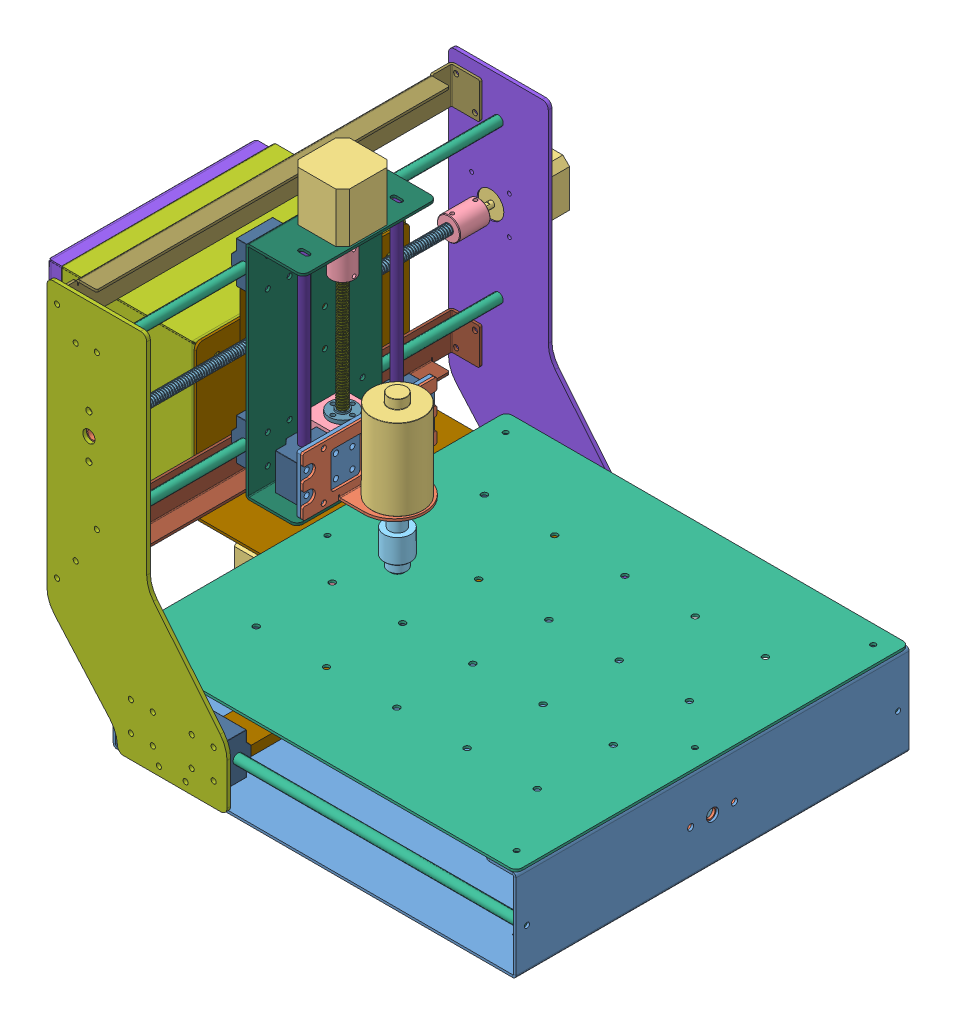
SolidWorks assembly MainAssem, configuration Default. Lengths in mm.
Overall size (517 348 374).
54 component instances, 27 part files, 15 mates.
Components (placement in the parent):
- SubAssem1-1: SubAssem1 [Default] at (69.9211 42.1369 -0.623) size (372 75 323) (flexible)
  - Base-1: Base [Default] at (143.0333 142.026 264.6541) size (331 75 323)
  - Pilow Bearing-1: Pilow Bearing [Default] at (306.5333 141.026 264.6541) x (0 0 -1) z (0 1 0) size (48 12 27)
  - Stepper Motor-1: Stepper Motor [Default] at (-41.9667 141.026 264.6541) x (0 -1 0) z (0 0 1) size (42 64 42)
  - Coupler-1: Coupler [Default] at (2.5333 141.026 264.6541) x (-1 0 0) z (0 0 -1) size (25 19 19)
  - Lead Screw 300mm-1: Lead Screw 300mm [Default] at (154.5333 141.026 264.6541) x (1 0 0) z (0 -0.67412 0.738622) size (304.2 8.95 8.95)
  - X-Y Rod-1: X-Y Rod [Default] at (143.0333 138.526 417.1541) x (0 0 -1) z (1 0 0) size (8 8 327)
  - X-Y Rod-2: X-Y Rod [Default] at (143.0333 138.526 112.1541) x (0 0 -1) z (1 0 0) size (8 8 327)
- SubAssem2-1: SubAssem2 [Default] at (9.4253 141.2294 165.1204) size (148 309 374) (flexible)
  - Leg B-1: Leg B [Default] at (29.5291 158.4335 263.9106) size (148 309 3)
  - Leg M-1: Leg M [Default] at (29.5291 158.4335 -66.0894) size (148 309 3)
  - X-Flat-1: X-Flat [Default] at (91.5291 15.4335 98.9106) size (32 8 327)
  - Pilow Bearing-1: Pilow Bearing [Default] at (23.0291 221.4335 262.4106) x (0 1 0) z (-1 0 0) size (48 12 27)
  - Stepper Motor-1: Stepper Motor [Default] at (23.0291 221.4335 -87.0894) x (0 -1 0) z (-1 0 0) size (42 64 42)
  - Coupler-1: Coupler [Default] at (23.0291 221.4335 -42.5894) x (0 0 -1) z (1 0 0) size (25 19 19)
  - Lead Screw 300mm-1: Lead Screw 300mm [Default] at (23.0291 221.4335 109.4106) x (0 0 -1) z (-0.881605 0.471987 0) size (304.2 8.95 8.95)
  - X-Y Rod-1: X-Y Rod [Default] at (29.5291 158.4335 98.9106) x (-0.696573 -0.717486 0) z (0 0 1) size (8 8 327)
  - X-Y Rod-2: X-Y Rod [Default] at (29.5291 284.4335 98.9106) x (0.999994 -0.003352 0) z (0 0 1) size (8 8 327)
  - linear Bearing-1: linear Bearing [Default] at (66.5291 39.4335 251.4106) x (0 -1 0) z (1 0 0) size (34 22 30)
  - linear Bearing-2: linear Bearing [Default] at (66.5291 39.4335 -53.5894) x (0 1 0) z (1 0 0) size (34 22 30)
  - linear Bearing-3: linear Bearing [Default] at (116.5291 39.4335 251.4106) x (0 -1 0) z (1 0 0) size (34 22 30)
  - linear Bearing-4: linear Bearing [Default] at (116.5291 39.4335 -53.5894) x (0 1 0) z (1 0 0) size (34 22 30)
  - Stiffner D-2: Stiffner D [Default] at (3.5291 117.4335 98.9106) x (0 1 0) z (0 0 1) size (30 25 327)
  - Stiffner U-1: Stiffner U [Default] at (3.5291 292.4335 98.9106) x (0 1 0) z (0 0 1) size (30 25 327)
  - X-Axis Block-1: X-Axis Block [Default] at (91.5291 44.4335 98.9106) x (0 0 -1) z (1 0 0) size (45 45 30)
  - Nut-1: Nut [Default] at (103.7791 41.9335 98.9106) x (-1 0 0) z (0 0 1) size (14.5 22 22)
- SubAssem3-1: SubAssem3 [Default] at (-6.2695 270.9573 128.328) size (92 223 110) (flexible)
  - Z Base R-1: Z Base R [Default] at (79.7238 91.7056 135.7031) size (47 182 110)
  - Stepper Motor-2: Stepper Motor [Default] at (80.7238 202.2056 135.7031) x (-1 0 0) z (0 0 1) size (42 64 42)
  - Pilow Bearing-1: Pilow Bearing [Default] at (80.7238 2.7056 135.7031) x (0 0 -1) z (1 0 0) size (48 12 27)
  - Coupler-1: Coupler [Default] at (80.7238 157.7056 135.7031) x (0 1 0) z (0 0 -1) size (25 19 19)
  - Lead Screw 150mm-1: Lead Screw 150mm [Default] at (80.7238 80.7056 135.7031) x (0 1 0) z (-0.624103 0 0.781342) size (153.6 8.95 8.95)
  - Z Rod-1: Z Rod [Default] at (87.2238 91.7056 173.7031) x (1 0 0) z (0 1 0) size (8 8 178)
  - Z Rod-2: Z Rod [Default] at (87.2238 91.7056 97.7031) x (1 0 0) z (0 -1 0) size (8 8 178)
  - linear Bearing-1: linear Bearing [Default] at (45.2238 154.7056 105.7031) x (0 1 0) z (0 0 1) size (34 22 30)
  - linear Bearing-2: linear Bearing [Default] at (45.2238 154.7056 165.7031) x (0 1 0) z (0 0 1) size (34 22 30)
  - linear Bearing-3: linear Bearing [Default] at (45.2238 28.7056 105.7031) x (0 1 0) z (0 0 1) size (34 22 30)
  - linear Bearing-4: linear Bearing [Default] at (45.2238 28.7056 165.7031) x (0 1 0) z (0 0 1) size (34 22 30)
  - Y-Axis Block-1: Y-Axis Block [Default] at (38.7238 91.7056 135.7031) x (0 1 0) z (0 0 1) size (45 45 30)
  - Nut-2: Nut [Default] at (38.7238 91.7056 147.9531) x (0 0 -1) z (0 1 0) size (14.5 22 22)
- SubAssem4-1: SubAssem4 [Default] at (55.1581 222.9704 193.2806) size (85 126 110) (flexible)
  - Z Plate-1: Z Plate [Default] at (38.2962 79.6925 70.7504) x (0 0 -1) z (1 0 0) size (110 48 3)
  - linear Bearing-1: linear Bearing [Default] at (25.7962 79.6925 32.7504) x (0 0 1) z (0 -1 0) size (34 22 30)
  - linear Bearing-2: linear Bearing [Default] at (25.7962 79.6925 108.7504) x (0 0 1) z (0 -1 0) size (34 22 30)
  - Motor Clamp-1: Motor Clamp [Default] at (41.7962 79.6925 70.7504) x (0 0 -1) z (1 0 0) size (110 48 47)
  - DC Motor-1: DC Motor [Default] at (64.2962 86.6925 70.7504) x (0 1 0) z (1 0 0) size (92.8 42 42)
  - Z-Axis Block-1: Z-Axis Block [Default] at (20.7962 78.6925 70.7504) x (0 0 -1) z (0 1 0) size (35 35 30)
  - Nut-1: Nut [Default] at (19.2962 90.9425 70.7504) x (0 -1 0) z (1 0 0) size (14.5 22 22)
  - Chuck-1: Chuck [Default] at (64.2962 35.6925 70.7504) x (-0.363163 0 -0.931726) z (0.931726 0 -0.363163) size (22 47 22)
- Bed-2: Bed [Default] at (212.9543 222.6629 264.031) x (0 0 -1) z (1 0 0) size (323 2 331)
- Panel-1: Panel [Default] at (59.5064 174.7873 160.1001) x (0 0 1) z (-1 0 0) size (175.31 185 186)
  - Panel box-1: Panel box [Default] at (49.431 101.8756 74.052) size (175.31 125.01 123.8)
  - Door-1: Door [Default] at (49.431 101.8756 198.052) x (-1 0 0) z (0 0 -1) size (170.3 120.01 14)
  - Bracket-1: Bracket [Default] at (49.431 101.8756 74.052) x (-1 0 0) z (0 0 -1) size (175 185 62)
Mates (geometry in assembly coordinates):
- Concentric1: concentric aligned: cylinder of SubAssem1-1/X-Y Rod-2 through (376.4543 180.6629 111.531) axis (-1 0 0) radius 4; cylinder of SubAssem2-1/linear Bearing-4 through (140.9543 180.6629 111.531) axis (-1 0 0) radius 4
- Concentric2: concentric aligned: cylinder of SubAssem1-1/X-Y Rod-1 through (376.4543 180.6629 416.531) axis (-1 0 0) radius 4; cylinder of SubAssem2-1/linear Bearing-1 through (90.9543 180.6629 416.531) axis (-1 0 0) radius 4
- Distance1: distance = 1 mm anti-aligned: plane of SubAssem2-1/X-Axis Block-1 through (85.9543 185.6629 264.031) normal (-1 0 0); plane of SubAssem1-1/Coupler-1 through (84.9543 183.1629 264.031) normal (1 0 0)
- Concentric3: concentric aligned: cylinder of SubAssem2-1/X-Y Rod-2 through (38.9543 425.6629 427.531) axis (0 0 -1) radius 4; cylinder of SubAssem3-1/linear Bearing-2 through (38.9543 425.6629 309.031) axis (0 0 -1) radius 4
- Concentric4: concentric aligned: cylinder of SubAssem2-1/X-Y Rod-1 through (38.9543 299.6629 427.531) axis (0 0 -1) radius 4; cylinder of SubAssem3-1/linear Bearing-3 through (38.9543 299.6629 249.031) axis (0 0 -1) radius 4
- Coincident2: coincident anti-aligned: plane of SubAssem2-1/Stiffner U-1 through (12.9543 433.6629 264.031) normal (0 0 1); plane of SubAssem3-1/Coupler-1 through (74.4543 428.6629 264.031) normal (0 0 -1)
- Concentric5: concentric anti-aligned: cylinder of SubAssem3-1/Z Rod-1 through (80.9543 451.6629 302.031) axis (0 -1 0) radius 4; cylinder of SubAssem4-1/linear Bearing-2 through (80.9543 287.6629 302.031) axis (0 1 0) radius 4
- Concentric6: concentric aligned: cylinder of SubAssem3-1/Z Rod-2 through (80.9543 273.6629 226.031) axis (0 1 0) radius 4; cylinder of SubAssem4-1/linear Bearing-1 through (80.9543 287.6629 226.031) axis (0 1 0) radius 4
- Distance2: distance = 1 mm anti-aligned: plane of SubAssem4-1/Z-Axis Block-1 through (75.9543 286.6629 264.031) normal (0 -1 0); plane of SubAssem3-1/Pilow Bearing-1 through (74.4543 285.6629 264.031) normal (0 1 0)
- Coincident3: coincident aligned: cylinder of SubAssem1-1/Base-1 through (363.9543 146.6619 264.031) axis (0 1 0) radius 2.1; circle of Bed-2
- Concentric8: concentric anti-aligned: cylinder of SubAssem1-1/Base-1 through (61.9543 146.6619 264.031) axis (0 1 0) radius 2.1; cylinder of Bed-2 through (61.9543 223.6629 264.031) axis (0 -1 0) radius 2.1
- Coincident4: coincident anti-aligned: plane of SubAssem1-1/Base-1 through (212.9543 221.6629 264.031) normal (0 1 0); plane of Bed-2 through (52.4543 221.6629 420.531) normal (0 -1 0)
- Concentric9: concentric anti-aligned: cylinder of SubAssem1-1/Base-1 through (49.4543 205.2902 135.531) axis (-1 0 0) radius 2.1; cylinder of Panel-1/Bracket-1 through (-14.5467 205.2902 135.531) axis (1 0 0) radius 2.1
- Concentric10: concentric anti-aligned: cylinder of SubAssem1-1/Base-1 through (49.4543 163.0356 218.531) axis (-1 0 0) radius 2.1; cylinder of Panel-1/Bracket-1 through (-14.5467 163.0356 218.531) axis (1 0 0) radius 2.1
- Coincident5: coincident anti-aligned: plane of SubAssem1-1/Base-1 through (47.4543 184.1629 264.031) normal (-1 0 0); plane of Panel-1/Bracket-1 through (47.4543 276.6629 209.531) normal (1 0 0)
